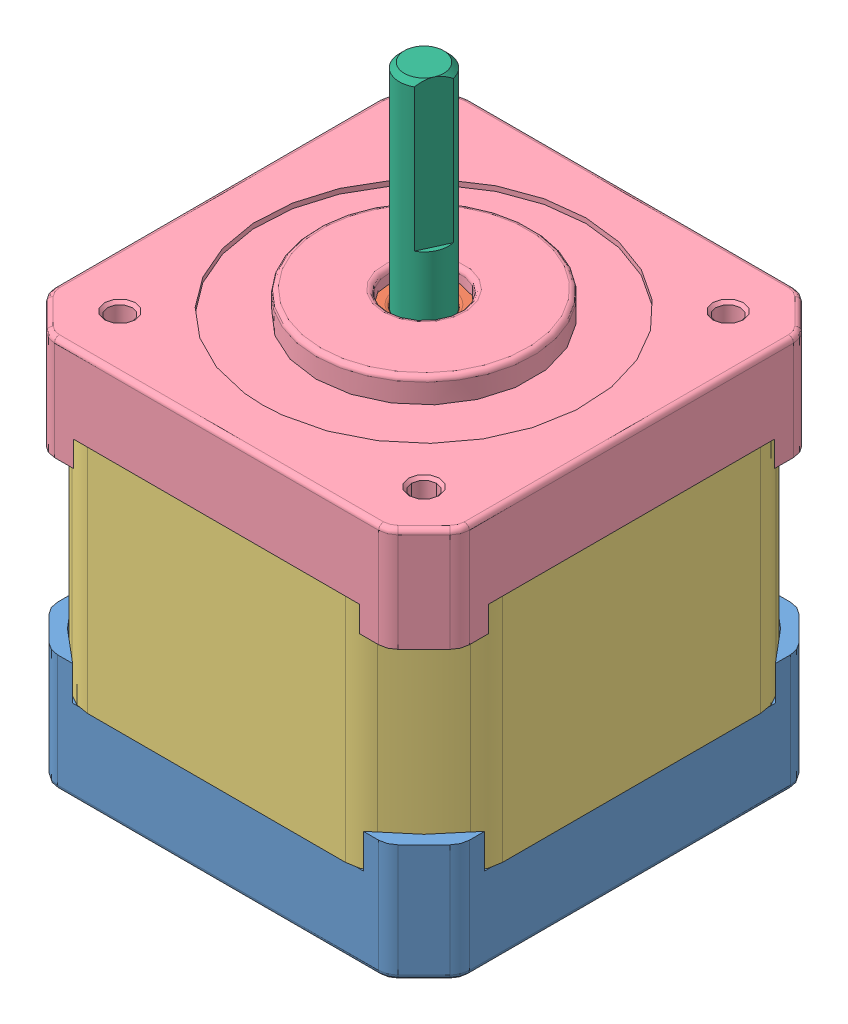
SolidWorks assembly 17HM15-0904S, configuration По умолчанию. Lengths in mm.
Overall size (42.3 62 42.3).
10 component instances, 6 part files, 16 mates.
Components (placement in the parent):
- nema17_bottom_40mm-1: nema17_bottom_40mm [По умолчанию] at origin size (42 12 42)
- radial ball bearing_68_din-1: radial ball bearing_68_din [DIN 625 - 625 - 8,SI,NC,8_68] at (0 5 0) x (0 -1 0) z (0 0 1) size (5 16 16)
- nema17_middle_40mm-1: nema17_middle_40mm [По умолчанию] at (0 8.5 0) size (42.3 23.5 42.3)
- nema17_top_40mm-1: nema17_top_40mm [По умолчанию] at (0 32 0) size (42.3 12.6 42.3)
- radial ball bearing_68_din-3: radial ball bearing_68_din [DIN 625 - 625 - 8,SI,NC,8_68] at (0 38.1 0) x (0 1 0) z (0 0 1) size (5 16 16)
- countersunk flat head cross recess screw_din-1: countersunk flat head cross recess screw_din [ISO 7046-1 - M3 x 30 - Z --- 30N] at (15.5 0.6 15.5) x (0 1 0) z (0.546944 0 -0.837169) size (30 5.5 5.5)
- countersunk flat head cross recess screw_din-2: countersunk flat head cross recess screw_din [ISO 7046-1 - M3 x 25 - Z --- 25N] at (15.5 0.6 -15.5) x (0 1 0) z (0.546944 0 -0.837169) size (25 5.5 5.5)
- countersunk flat head cross recess screw_din-3: countersunk flat head cross recess screw_din [ISO 7046-1 - M3 x 30 - Z --- 30N] at (-15.5 0.6 15.5) x (0 1 0) z (0.546944 0 -0.837169) size (30 5.5 5.5)
- countersunk flat head cross recess screw_din-4: countersunk flat head cross recess screw_din [ISO 7046-1 - M3 x 30 - Z --- 30N] at (-15.5 0.6 -15.5) x (0 1 0) z (0.546944 0 -0.837169) size (30 5.5 5.5)
- nema17_shaft_40mm-1: nema17_shaft_40mm [По умолчанию] at (0 2 0) x (-0.412738 0 0.91085) z (-0.91085 0 -0.412738) size (5 60 5)
Mates (geometry in assembly coordinates):
- Совпадение1: coincident anti-aligned: plane of nema17_bottom_40mm-1 through (0 2.5 0) normal (0 1 0); plane of radial ball bearing_68_din-1 through (7.7 2.5 0) normal (0 -1 0)
- Концентричный1: concentric anti-aligned: cylinder of nema17_bottom_40mm-1 through (0 2.5 0) axis (0 1 0) radius 8; cylinder of radial ball bearing_68_din-1 through (0 25.6375 0) axis (0 -1 0) radius 8
- Концентричный2: concentric aligned: cylinder of nema17_bottom_40mm-1 through (15.5 8.5 15.5) axis (0 -1 0) radius 1.25; cylinder of nema17_middle_40mm-1 through (15.5 32 15.5) axis (0 -1 0) radius 1.25
- Концентричный3: concentric aligned: cylinder of nema17_bottom_40mm-1 through (-15.5 8.5 -15.5) axis (0 -1 0) radius 1.25; cylinder of nema17_middle_40mm-1 through (-15.5 32 -15.5) axis (0 -1 0) radius 1.25
- Совпадение2: coincident anti-aligned: plane of nema17_bottom_40mm-1 through (0 8.5 0) normal (0 1 0); plane of nema17_middle_40mm-1 through (0 8.5 0) normal (0 -1 0)
- Концентричный4: concentric aligned: cylinder of nema17_middle_40mm-1 through (15.5 32 15.5) axis (0 -1 0) radius 1.25; cylinder of nema17_top_40mm-1 through (15.5 40 15.5) axis (0 -1 0) radius 1.25
- Концентричный5: concentric aligned: cylinder of nema17_middle_40mm-1 through (-15.5 32 -15.5) axis (0 -1 0) radius 1.25; cylinder of nema17_top_40mm-1 through (-15.5 40 -15.5) axis (0 -1 0) radius 1.25
- Совпадение3: coincident anti-aligned: plane of nema17_middle_40mm-1 through (0 32 0) normal (0 1 0); plane of nema17_top_40mm-1 through (0 32 0) normal (0 -1 0)
- Совпадение4: coincident anti-aligned: plane of nema17_top_40mm-1 through (0 40.6 0) normal (0 -1 0); plane of radial ball bearing_68_din-3 through (-7.7 40.6 0) normal (0 1 0)
- Концентричный6: concentric anti-aligned: cylinder of nema17_top_40mm-1 through (0 40.6 0) axis (0 -1 0) radius 8; cylinder of radial ball bearing_68_din-3 through (0 17.4625 0) axis (0 1 0) radius 8
- Совпадение5: coincident aligned: cone of nema17_bottom_40mm-1 through (15.5 0 15.5) axis (0 1 0); cone of countersunk flat head cross recess screw_din-1 through (15.5 1 15.5) axis (0 1 0)
- Совпадение6: coincident aligned: cone of nema17_bottom_40mm-1 through (15.5 0 -15.5) axis (0 1 0); cone of countersunk flat head cross recess screw_din-2 through (15.5 1 -15.5) axis (0 1 0)
- Совпадение7: coincident aligned: cone of nema17_bottom_40mm-1 through (-15.5 0 15.5) axis (0 1 0); cone of countersunk flat head cross recess screw_din-3 through (-15.5 1 15.5) axis (0 1 0)
- Совпадение8: coincident aligned: cone of nema17_bottom_40mm-1 through (-15.5 0 -15.5) axis (0 1 0); cone of countersunk flat head cross recess screw_din-4 through (-15.5 1 -15.5) axis (0 1 0)
- Концентричный8: concentric aligned: cylinder of nema17_top_40mm-1 through (0 42 0) axis (0 -1 0) radius 3.65; cylinder of nema17_shaft_40mm-1 through (0 62 0) axis (0 -1 0) radius 2.5
- Расстояние1: distance = 22 mm aligned: plane of nema17_shaft_40mm-1 through (0 62 0) normal (0 1 0); plane of nema17_top_40mm-1 through (0 40 0) normal (0 1 0)
